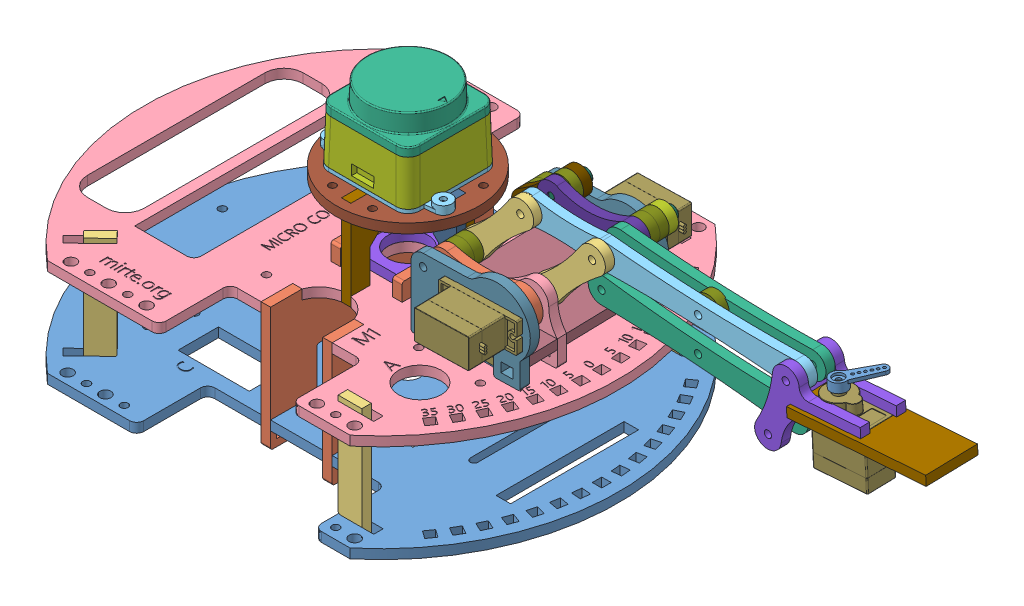
SolidWorks assembly Frame Only plus lidar, configuration Default. Lengths in mm.
Overall size (301.92 122.28 154).
51 component instances, 27 part files, 43 mates.
Components (placement in the parent):
- LAYER 1 New-1: LAYER 1 New [Default] at origin size (200 4 154)
- Motor frame 2-1: Motor frame 2 [Default] at (22.3044 -7.1 47) x (0 0 -1) z (0 -1 0) size (94 4 59.7)
- Motor frame 2-2: Motor frame 2 [Default] at (-3.6956 -7.1 47) x (0 0 -1) z (0 -1 0) size (94 4 59.7)
- Slide spacer-1: Slide spacer [Default] at (-58.0581 21.9 53.2858) x (0.71934 0 -0.694658) z (0.694658 0 0.71934) size (10 50.4 4)
- Slide spacer-2: Slide spacer [Default] at (-55.2795 21.9 -56.1631) x (0.71934 0 0.694658) z (-0.694658 0 0.71934) size (10 50.4 4)
- Slide spacer-3: Slide spacer [Default] at (48.8044 22.1644 -63) x (-1 0 0) z (0 0 -1) size (10 50.4 4)
- Slide spacer-5: Slide spacer [Default] at (48.8044 22.1644 67) x (-1 0 0) z (0 0 -1) size (10 50.4 4)
- LAYER 2 new-1: LAYER 2 new [Default] at (-116.6328 -60.1337 -160.0612) size (200 4 154)
- LD19.step-1: LD19.step [Default] at (11.3044 79.2 -0.099) x (1 0 0) z (0 1 0) size (53.95 46.29 31.3)
  - LD19_BASE.step-1: LD19_BASE.step [Default] at (0 -8.624 0) size (53.95 46.29 3.5)
  - LD19_EMITTER.step-1: LD19_EMITTER.step [Default] at (0 -8.5972 0) size (37.61 37.61 11.2)
  - LD19_BODY.step-1: LD19_BODY.step [Default] at (0 -8.5972 0) size (38.52 38.52 18.6)
- Pen Hole Lock-1: Pen Hole Lock [Default] at (-3.6956 45.2 12.5) size (44 4 25)
- Raiser-1: Raiser [Default] at (13.3044 41.2 -25.95) x (0 0 1) z (-1 0 0) size (52.07 38 4)
- Raiser 2-1: Raiser 2 [Default] at (33.8044 45.2 -1.915) size (45 38 4)
- platform-1: platform [Default] at (11.3044 75.2 0.085) x (0 0 -1) z (1 0 0) size (60 4 60)
- microservoSG90-1: microservoSG90 [Default] at (59.4544 29.6 -0.3) x (-1 0 0) z (0 0 -1) size (32.3 29.8 12.5)
- Arm-1: Arm [Default] at (114.6165 56.2 65.877) x (-0.999708 0 0.024175) z (-0.024175 0 -0.999708) size (197.53 59.85 96.4)
  - Base (Finger Joint Connection)-1: Base (Finger Joint Connection) [Default] at (25.9477 4 37.3679) x (1 0 0) z (0 -1 0) size (45 60 4)
  - Side Panel (Finger Joint Connection)-1: Side Panel (Finger Joint Connection) [Default] at (25.9477 4 93.3679) size (49.14 35.14 4)
  - Side Panel (Finger Joint Connection)-2: Side Panel (Finger Joint Connection) [Default] at (25.9477 4 37.3679) size (49.14 35.14 4)
  - microservoSG90-3: microservoSG90 [Default] at (41.0477 14 19.1679) x (1 0 0) z (0 -1 0) size (32.3 29.8 12.5)
  - socket head cap screw_iso-3: socket head cap screw_iso [ISO 4762 M3 x 20 - 20N] at (65.9477 19 100.3679) x (0 0 -1) z (0.947312 0.320314 0) size (23 5.5 5.5)
  - 4mm Spacer-2: 4mm Spacer [Default] at (65.9477 19 93.3679) x (0.6336 -0.773661 0) z (0.773661 0.6336 0) size (11 4 11)
  - Stabilizer Triangle-1: Stabilizer Triangle [Default] at (22.5845 15.5383 72.9679) x (0.943404 0.331646 0) z (0 0 1) size (41 32.57 4)
  - 4mm Spacer-3: 4mm Spacer [Default] at (15.4309 35.8875 84.9679) x (-0.98853 -0.151025 0) z (0.151025 -0.98853 0) size (11 4 11)
  - socket head cap screw_iso-4: socket head cap screw_iso [ISO 4762 M3 x 16 - 16N] at (15.4309 35.8875 91.9679) x (0 0 -1) z (0.778189 0.62803 0) size (19 5.5 5.5)
  - X-Link-1: X-Link [Default] at (65.9477 19 81.3679) x (0.666489 0.745515 0) z (0.745515 -0.666489 0) size (11 4 36)
  - 4mm Spacer-4: 4mm Spacer [Default] at (65.9477 19 89.3679) x (0.6336 -0.773661 0) z (0.773661 0.6336 0) size (11 4 11)
  - SG90 - Micro Servo 9g - Tower Pro.2-1: SG90 - Micro Servo 9g - Tower Pro.2 [Peça] at (35.9477 14 83.5679) x (0.767364 -0.641212 0) z (0.641212 0.767364 0) size (19.5 3.8 6.9)
  - socket head cap screw_iso-5: socket head cap screw_iso [ISO 4762 M3 x 12 - 12N] at (47.3098 35.6622 88.3679) x (0 0 -1) z (0.947312 0.320314 0) size (15 5.5 5.5)
  - 4mm Spacer-5: 4mm Spacer [Default] at (15.4309 35.8875 80.9679) x (0.983445 -0.181209 0) z (0.181209 0.983445 0) size (11 4 11)
  - 4mm Spacer-6: 4mm Spacer [Default] at (47.3098 35.6622 81.3679) x (0.937465 0.34808 0) z (-0.34808 0.937465 0) size (11 4 11)
  - Y-Servo Link-1: Y-Servo Link [Default] at (50.9155 14.982 45.7679) x (0.065468 -0.997855 0) z (0 0 1) size (15.2 43.1 4)
  - Y-Link 1-1: Y-Link 1 [Default] at (65.8833 15.964 57.7679) x (0.729583 0.683893 0) z (0.683893 -0.729583 0) size (11 4 41)
  - SG90 - Micro Servo 9g - Tower Pro.2-2: SG90 - Micro Servo 9g - Tower Pro.2 [Peça] at (35.9477 14 51.1679) x (-0.768689 0.639623 0) z (0.639623 0.768689 0) size (19.5 3.8 6.9)
  - 4mm Spacer-7: 4mm Spacer [Default] at (65.8833 15.964 53.7679) x (0.985317 0.170736 0) z (-0.170736 0.985317 0) size (11 4 11)
  - 4mm Spacer-8: 4mm Spacer [Default] at (65.8833 15.964 57.7679) x (0.265682 0.964061 0) z (-0.964061 0.265682 0) size (11 4 11)
  - Centre Y link base connector-1: Centre Y link base connector [Default] at (25.9477 4 53.3679) size (45 27.5 4)
  - Y-Link 1-2: Y-Link 1 [Default] at (35.9477 14 57.3679) x (0.729583 0.683893 0) z (0.683893 -0.729583 0) size (11 4 41)
  - Y-long link-1: Y-long link [Default] at (45.3665 37.8515 61.3679) x (-0.065468 0.997855 0) z (0.997855 0.065468 0) size (11 4 121)
  - X-long link-1: X-long link [Default] at (15.4309 35.8875 68.9679) x (-0.065468 0.997855 0) z (0.997855 0.065468 0) size (11 4 91)
  - X-Servo Link-3: X-Servo Link [Default] at (25.6893 24.9437 84.9679) x (0.729583 0.683893 0) z (0 0 1) size (15.2 43.1 4)
  - microservoSG90-4: microservoSG90 [Default] at (41.0477 14 115.5679) x (1 0 0) z (0 1 0) size (32.3 29.8 12.5)
  - 4mm Spacer-9: 4mm Spacer [Default] at (-24.4833 33.2687 69.3679) x (-0.98853 -0.151025 0) z (0.151025 -0.98853 0) size (11 4 11)
  - X-long link-2: X-long link [Default] at (22.5845 15.5383 68.9679) x (-0.098515 0.995136 0) z (0.995136 0.098515 0) size (11 4 91)
  - Horizontalizer Connector-1: Horizontalizer Connector [Default] at (-64.3975 30.65 76.9679) x (-0.998775 0.049489 0) z (0 0 -1) size (44.5 33.6 4)
  - Horizontalizer Connector-2: Horizontalizer Connector [Default] at (-64.3975 30.65 61.3679) x (-0.998775 0.049489 0) z (0 0 -1) size (44.5 33.6 4)
  - Gripper Servo Mount-1: Gripper Servo Mount [Default] at (-71.2656 23.381 73.1014) x (-0.998775 0.049489 0) z (0 0 1) size (57.42 4 22.42)
  - microservoSG90-5: microservoSG90 [Default] at (-83.6504 1.7674 66.9014) x (-0.998775 0.049489 0) z (0 0 -1) size (32.3 29.8 12.5)
  - SG90 - Micro Servo 9g - Tower Pro.2-3: SG90 - Micro Servo 9g - Tower Pro.2 [Peça] at (-76.973 33.4758 66.9014) x (0.486267 -0.024095 -0.873478) z (0.872408 -0.043228 0.486863) size (19.5 3.8 6.9)
Mates (geometry in assembly coordinates):
- Coincident9: coincident aligned: plane of Motor frame 2-1 through (26.3044 -7.1 -47) normal (0 0 -1); plane of Motor frame 2-2 through (0.3044 -7.1 -47) normal (0 0 -1)
- Coincident10: coincident aligned: plane of Motor frame 2-1 through (26.3044 22 47) normal (0 -1 0); plane of Motor frame 2-2 through (0.3044 22 47) normal (0 -1 0)
- Coincident11: coincident anti-aligned: plane of LAYER 1 New-1 through (0 4 0) normal (0 1 0); plane of Motor frame 2-1 through (26.3044 4 47) normal (0 -1 0)
- Coincident12: coincident aligned: plane of LAYER 1 New-1 through (0 0 47) normal (0 0 1); plane of Motor frame 2-2 through (0.3044 -7.1 47) normal (0 0 1)
- Coincident13: coincident anti-aligned: plane of LAYER 1 New-1 through (0.3044 -14.5602 47.64) normal (-1 0 0); plane of Motor frame 2-2 through (0.3044 -7.1 47) normal (1 0 0)
- Coincident14: coincident anti-aligned: plane of LAYER 1 New-1 through (22.3044 -14.5602 47.64) normal (1 0 0); plane of Motor frame 2-1 through (22.3044 -7.1 47) normal (-1 0 0)
- Coincident29: coincident anti-aligned: plane of LAYER 1 New-1 through (-59.7394 -13.9983 60.47) normal (-0.71934 0 0.694658); plane of Slide spacer-1 through (-59.7394 21.9 60.47) normal (0.71934 0 -0.694658)
- Coincident30: coincident: line of LAYER 1 New-1 through (-66.9328 4 67.4166) axis (0.71934 0 -0.694658); plane of Slide spacer-1 through (-55.2795 21.9 56.1631) normal (0.694658 0 0.71934)
- Coincident31: coincident: point of LAYER 1 New-1; line of Slide spacer-1 through (-59.7394 0 60.47) axis (-0.694658 0 -0.71934)
- Coincident32: coincident anti-aligned: line of LAYER 1 New-1 through (-59.7394 0 -60.47) axis (-0.694658 0 0.71934); line of Slide spacer-2 through (-62.5181 0 -57.5927) axis (0.694658 0 -0.71934)
- Coincident33: coincident anti-aligned: plane of LAYER 1 New-1 through (-62.5181 -13.9983 -57.5927) normal (-0.71934 0 -0.694658); plane of Slide spacer-2 through (-62.5181 21.9 -57.5927) normal (0.71934 0 0.694658)
- Coincident34: coincident: line of LAYER 1 New-1 through (-69.7115 4 -64.5392) axis (0.71934 0 0.694658); plane of Slide spacer-2 through (-58.0581 21.9 -53.2858) normal (-0.694658 0 0.71934)
- Coincident35: coincident aligned: plane of LAYER 1 New-1 through (48.8044 0 0) normal (-1 0 0); plane of Slide spacer-5 through (48.8044 22.1644 63) normal (-1 0 0)
- Coincident36: coincident anti-aligned: plane of LAYER 1 New-1 through (53.8044 -13.9983 67) normal (0 0 -1); plane of Slide spacer-5 through (48.8044 22.1644 67) normal (0 0 1)
- Coincident39: coincident: plane of LAYER 1 New-1 through (0 0 0) normal (0 -1 0); line of Slide spacer-5 through (49.54 0 63) axis (0 0 1)
- Coincident40: coincident aligned: plane of LAYER 1 New-1 through (48.8044 0 0) normal (-1 0 0); plane of Slide spacer-3 through (48.8044 22.1644 -67) normal (-1 0 0)
- Coincident42: coincident anti-aligned: plane of LAYER 1 New-1 through (53.8044 -13.9983 -67) normal (0 0 1); plane of Slide spacer-3 through (48.8044 22.1644 -67) normal (0 0 -1)
- Coincident43: coincident: plane of LAYER 1 New-1 through (0 0 0) normal (0 -1 0); line of Slide spacer-3 through (49.54 0 -67) axis (0 0 1)
- Coincident44: coincident anti-aligned: plane of Motor frame 2-1 through (22.3044 -7.1 47) normal (-1 0 0); plane of LAYER 2 new-1 through (22.3044 45.2 -160.0612) normal (1 0 0)
- Coincident45: coincident anti-aligned: plane of Motor frame 2-1 through (26.3044 -7.1 17.5) normal (0 0 1); plane of LAYER 2 new-1 through (-116.6328 45.2 17.5) normal (0 0 -1)
- Coincident46: coincident anti-aligned: plane of Motor frame 2-1 through (26.3044 41.2 -47) normal (0 1 0); plane of LAYER 2 new-1 through (-116.6328 41.2 -160.0612) normal (0 -1 0)
- Parallel7: parallel anti-aligned: plane of Motor frame 2-1 through (26.3044 52.6 47) normal (0 1 0); plane of LD19.step-1/LD19_BASE.step-1 through (11.3044 79.2 -3.825) normal (0 -1 0)
- Coincident48: coincident anti-aligned: plane of Motor frame 2-1 through (26.3044 -7.1 12.5) normal (0 0 -1); plane of Pen Hole Lock-1 through (-3.6956 49.2 12.5) normal (0 0 1)
- Coincident49: coincident aligned: plane of Motor frame 2-1 through (26.3044 -7.1 47) normal (1 0 0); plane of Pen Hole Lock-1 through (26.3044 49.2 2) normal (1 0 0)
- Coincident50: coincident anti-aligned: plane of LAYER 2 new-1 through (-116.6328 45.2 -160.0612) normal (0 1 0); plane of Pen Hole Lock-1 through (-3.6956 45.2 12.5) normal (0 -1 0)
- Coincident51: coincident anti-aligned: plane of LAYER 2 new-1 through (-116.6328 45.2 -21.95) normal (0 0 -1); plane of Raiser-1 through (9.3044 41.2 -21.95) normal (0 0 1)
- Coincident52: coincident aligned: plane of LAYER 2 new-1 through (-116.6328 41.2 -160.0612) normal (0 -1 0); plane of Raiser-1 through (9.3044 41.2 -25.95) normal (0 -1 0)
- Coincident53: coincident: line of LAYER 2 new-1 through (9.3044 45.2 -26.1222) axis (0 -1 0); plane of Raiser-1 through (9.3044 41.2 -25.95) normal (-1 0 0)
- Coincident54: coincident anti-aligned: plane of Raiser-1 through (9.3044 41.2 2.085) normal (0 0 -1); plane of Raiser 2-1 through (33.8044 45.2 2.085) normal (0 0 1)
- Coincident55: coincident anti-aligned: plane of Raiser-1 through (9.3044 69.2 -25.95) normal (0 -1 0); plane of Raiser 2-1 through (13.3044 69.2 2.085) normal (0 1 0)
- Coincident63: coincident anti-aligned: plane of Raiser 2-1 through (33.8044 45.2 2.085) normal (1 0 0); plane of platform-1 through (33.8044 75.2 0.085) normal (-1 0 0)
- Coincident64: coincident anti-aligned: plane of Pen Hole Lock-1 through (33.8044 49.2 2) normal (-1 0 0); plane of Raiser 2-1 through (33.8044 45.2 2.085) normal (1 0 0)
- Coincident65: coincident aligned: line of Raiser 2-1 through (13.3044 79.2 2.085) axis (0 -1 0); line of platform-1 through (13.3044 79.2 2.085) axis (0 -1 0)
- Coincident66: coincident anti-aligned: plane of Raiser-1 through (9.3044 75.2 -25.95) normal (0 1 0); plane of platform-1 through (11.3044 75.2 0.085) normal (0 -1 0)
- Concentric2: concentric anti-aligned: cylinder of LD19.step-1/LD19_BASE.step-1 through (34.7044 150.7487 8.525) axis (0 -1 0) radius 1.25; cylinder of platform-1 through (34.7044 75.2 8.525) axis (0 1 0) radius 1.5
- Coincident67: coincident anti-aligned: plane of LD19.step-1/LD19_BASE.step-1 through (11.3044 79.2 -3.825) normal (0 -1 0); plane of platform-1 through (11.3044 79.2 0.085) normal (0 1 0)
- Concentric3: concentric anti-aligned: circle of LD19.step-1/LD19_BASE.step-1; cylinder of platform-1 through (-12.0956 75.2 8.525) axis (0 1 0) radius 1.5
- Coincident69: coincident anti-aligned: plane of LAYER 2 new-1 through (70.7544 45.2 -160.0612) normal (-1 0 0); plane of microservoSG90-1 through (70.7544 45.2 -6.5) normal (1 0 0)
- Coincident73: coincident: plane of LAYER 2 new-1 through (-116.6328 45.2 -160.0612) normal (0 1 0); line of microservoSG90-1 through (43.8044 45.2 5.9) axis (1 0 0)
- Coincident74: coincident: plane of LAYER 2 new-1 through (-116.6328 45.2 -160.0612) normal (0 1 0); line of microservoSG90-1 through (75.1044 45.2 -6.5) axis (-1 0 0)
- Distance2: distance = 16 mm: plane of microservoSG90-1 through (70.7544 45.2 5.9) normal (0 0 1); line of LAYER 2 new-1 through (61.3044 45.2 21.9) axis (1 0 0)
- Concentric4: concentric aligned: cylinder of microservoSG90-1 through (64.5544 59.4 -0.3) axis (0 -1 0) radius 2.45; circle of Arm-1/Base (Finger Joint Connection)-1
- Coincident75: coincident anti-aligned: plane of microservoSG90-1 through (58.8044 56.2 -0.3) normal (0 1 0); plane of Arm-1/Base (Finger Joint Connection)-1 through (87.773 56.2 29.1473) normal (0 -1 0)
